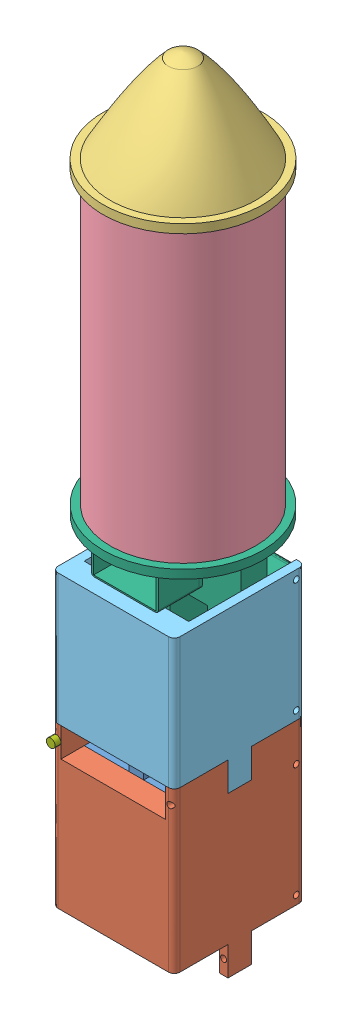
SolidWorks assembly little_part_assembly3, configuration 預設. Lengths in mm.
Overall size (77.43 273.72 77.43).
8 component instances, 8 part files, 21 mates.
Components (placement in the parent):
- little_connect2-1: little_connect2 [預設] at (2.9269 -5.6523 112) size (36 97.5 37)
- little_connect_part2_3-1: little_connect_part2_3 [預設] at (-2.5277 -23.7432 119) x (1 0 0) z (0 0 -1) size (42 65 45)
- lib_head_3-1: lib_head_3 [預設] at (2.9269 177.3477 100) x (-0.771162 0 0.636639) z (0.636639 0 0.771162) size (55 65.72 55)
- littlebody-1: littlebody [預設] at (2.9269 77.3477 100) x (0.874199 0 0.485567) z (-0.485567 0 0.874199) size (50 100 50)
- little_connect_part2_3_first-1: little_connect_part2_3_first [預設] at (-2.5277 31.2568 119) x (1 0 0) z (0 0 -1) size (42.3 55 46.77)
- lib_tail_3-2: lib_tail_3 [預設] at (2.9269 77.3477 100) size (55 82.65 55.77)
- connect_part1-1: connect_part1 [預設] at (-16.5731 9.3477 79.0057) x (0.65968 0.751546 0) z (0 0 1) size (3 3 47)
- connect_part2-1: connect_part2 [預設] at (-16.5731 9.3477 77.0057) size (3 3 10)
Mates (geometry in assembly coordinates):
- 同軸心1: concentric: cylinder of little_connect2-1 through (-10.0731 1.3477 82) axis (-1 0 0) radius 1.025; cylinder of little_connect_part2_3-1 through (27.4269 1.3477 82) axis (-1 0 0) radius 1.025
- 同軸心2: concentric: cylinder of little_connect2-1 through (-10.0731 -37.6523 82) axis (-1 0 0) radius 1.025; cylinder of little_connect_part2_3-1 through (27.4269 -37.6523 82) axis (-1 0 0) radius 1.025
- 重合/共線/共點1: coincident: plane of little_connect2-1 through (-15.0731 4.3477 79) normal (-1 0 0); plane of little_connect_part2_3-1 through (-15.0731 9.3477 116) normal (1 0 0)
- 同軸心3: concentric: cylinder of lib_head_3-1 through (2.9269 162.8477 100) axis (0 1 0) radius 21.75; cylinder of littlebody-1 through (2.9269 177.3477 100) axis (0 -1 0) radius 22
- 重合/共線/共點2: coincident: plane of lib_head_3-1 through (2.9269 177.3477 100) normal (0 -1 0); plane of littlebody-1 through (2.9269 177.3477 100) normal (0 1 0)
- 同軸心5: concentric: cylinder of little_connect_part2_3-1 through (22.4269 9.3477 60.5) axis (0 0 1) radius 1.05; cylinder of little_connect_part2_3_first-1 through (22.4269 9.3477 95.5) axis (0 0 1) radius 1.05
- 同軸心6: concentric: cylinder of little_connect_part2_3-1 through (-16.5731 9.3477 60.5) axis (0 0 1) radius 1.05; cylinder of little_connect_part2_3_first-1 through (-16.5731 9.3477 95.5) axis (0 0 1) radius 1.05
- 重合/共線/共點5: coincident: plane of little_connect_part2_3-1 through (23.9269 14.3477 105.5) normal (0 0 -1); plane of little_connect_part2_3_first-1 through (23.9269 4.3477 105.5) normal (0 0 1)
- 同軸心7: concentric: cylinder of littlebody-1 through (2.9269 177.3477 100) axis (0 -1 0) radius 22; cylinder of lib_tail_3-2 through (2.9269 90.8477 100) axis (0 -1 0) radius 21.75
- 重合/共線/共點6: coincident: plane of littlebody-1 through (2.9269 77.3477 100) normal (0 -1 0); plane of lib_tail_3-2 through (2.9269 77.3477 100) normal (0 1 0)
- 重合/共線/共點7: coincident: plane of little_connect2-1 through (2.9269 -5.6523 79) normal (0 0 -1); plane of lib_tail_3-2 through (2.9269 77.3477 79) normal (0 0 -1)
- 重合/共線/共點8: coincident: plane of little_connect_part2_3-1 through (20.9269 9.3477 116) normal (-1 0 0); plane of lib_tail_3-2 through (20.9269 74.3477 79) normal (1 0 0)
- 同軸心9: concentric: cylinder of little_connect_part2_3_first-1 through (27.4269 17.3477 82) axis (-1 0 0) radius 1.025; cylinder of lib_tail_3-2 through (26.5269 17.3477 82) axis (-1 0 0) radius 1.025
- 同軸心10: concentric: cylinder of littlebody-1 through (2.9269 177.3477 100) axis (0 -1 0) radius 22; cylinder of lib_tail_3-2 through (2.9269 90.8477 100) axis (0 -1 0) radius 21.75
- 重合/共線/共點10: coincident: plane of littlebody-1 through (2.9269 77.3477 100) normal (0 -1 0); plane of lib_tail_3-2 through (2.9269 77.3477 100) normal (0 1 0)
- 同軸心11: concentric: cylinder of little_connect_part2_3_first-1 through (27.4269 17.3477 82) axis (-1 0 0) radius 1.025; cylinder of lib_tail_3-2 through (26.5269 17.3477 82) axis (-1 0 0) radius 1.025
- 同軸心12: concentric: cylinder of little_connect_part2_3_first-1 through (27.4269 56.3477 82) axis (-1 0 0) radius 1.025; cylinder of lib_tail_3-2 through (26.5269 56.3477 82) axis (-1 0 0) radius 1.025
- 重合/共線/共點11: coincident: plane of little_connect_part2_3_first-1 through (20.9269 64.3477 116) normal (-1 0 0); plane of lib_tail_3-2 through (20.9269 74.3477 79) normal (1 0 0)
- 同軸心13: concentric: cylinder of little_connect_part2_3-1 through (-16.5731 9.3477 60.5) axis (0 0 1) radius 1.05; cylinder of connect_part1-1 through (-16.5731 9.3477 124.0057) axis (0 0 -1) radius 1
- 同軸心14: concentric: cylinder of connect_part1-1 through (-16.5731 9.3477 99.0057) axis (0 0 -1) radius 0.75; cylinder of connect_part2-1 through (-16.5731 9.3477 87.0057) axis (0 0 -1) radius 0.7
- 重合/共線/共點12: coincident: plane of connect_part1-1 through (-16.5731 9.3477 79.0057) normal (0 0 -1); plane of connect_part2-1 through (-16.5731 9.3477 79.0057) normal (0 0 1)
